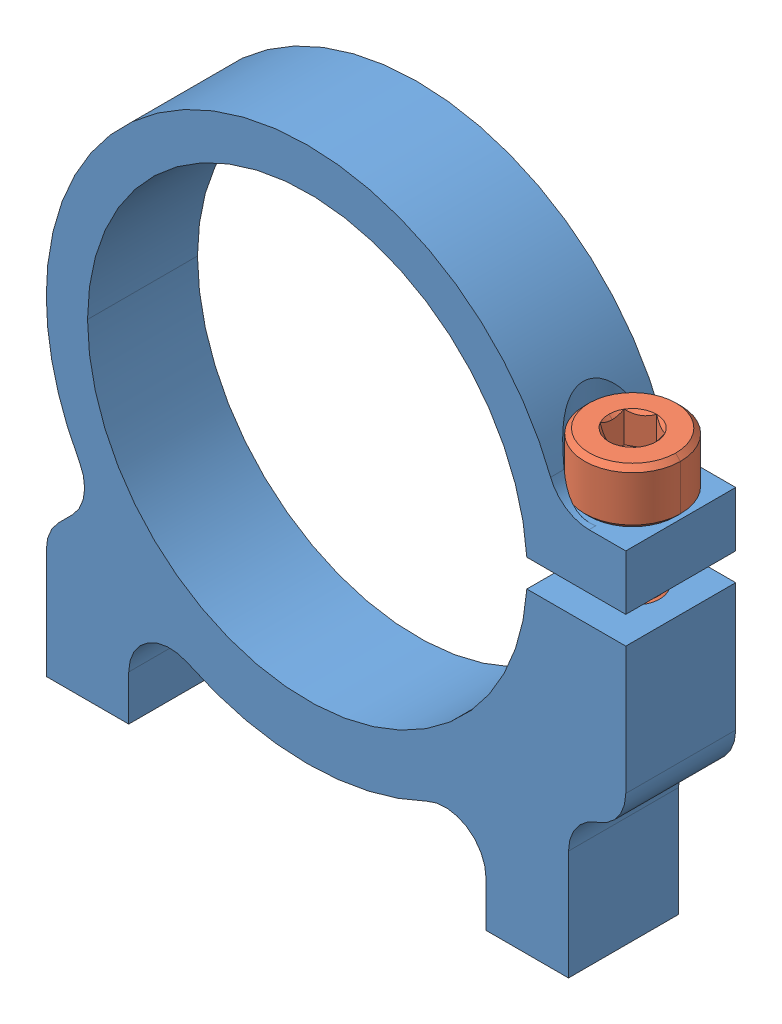
SolidWorks assembly 1400-0032-0032 assembly, configuration Default. Lengths in mm.
Overall size (42.19 43 8).
3 component instances, 2 part files, 0 mates.
Components (placement in the parent):
- 1400-0032-0032 assembly.STEP-1: 1400-0032-0032 assembly.STEP [Default] at origin size (42.19 43 8)
  - 1400-0032-0032.STEP-1: 1400-0032-0032.STEP [Default] at (-9.2052 9.5558 -4.9517) size (42.17 43 8)
  - 2800-0004-0012_90128A207.STEP-1: 2800-0004-0012_90128A207.STEP [默认] at (10.4635 2.5558 -0.9517) x (0.999977 0 0.006769) z (0 -1 0) size (7 7 16.01)
